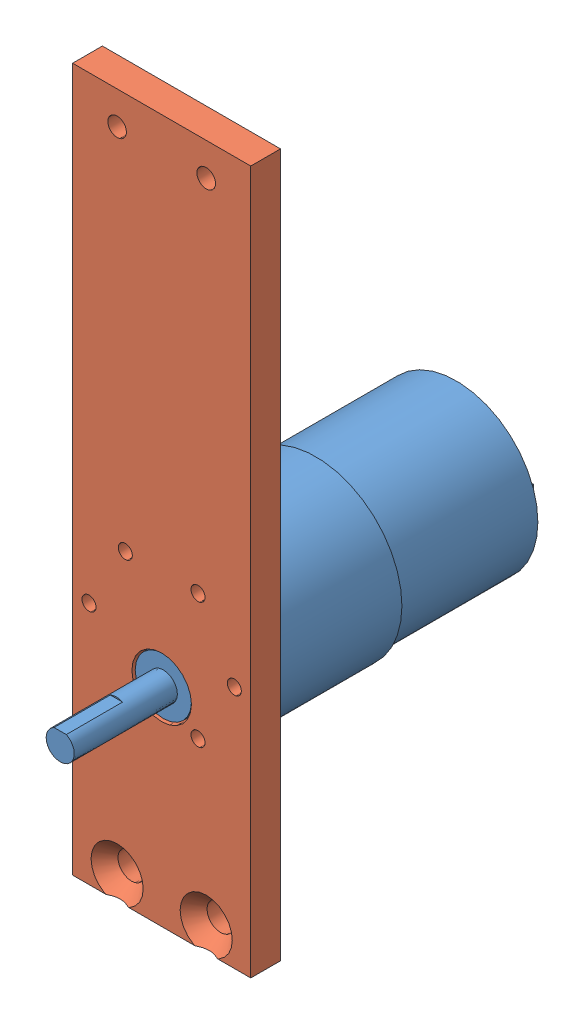
SolidWorks assembly Motor Montado, configuration Predeterminado. Lengths in mm.
Overall size (38 195 89.5).
2 component instances, 2 part files, 3 mates.
Components (placement in the parent):
- Motores Pololu-1: Motores Pololu [Predeterminado] at (-0.3863 2.7426 79.75) size (36.8 36.8 89.5)
- soporte motor-1: soporte motor [Predeterminado] at (-0.3863 25.7426 109.425) size (38 195 6.35)
Mates (geometry in assembly coordinates):
- Paralelo1: parallel aligned: cylinder of Motores Pololu-1 through (7.3637 16.166 101.25) axis (0 0 1) radius 1.5; cylinder of soporte motor-1 through (15.1137 2.7426 87.2) axis (0 0 1) radius 1.5
- Coincidente1: coincident anti-aligned: plane of Motores Pololu-1 through (-0.3863 2.7426 106.25) normal (0 0 1); plane of soporte motor-1 through (-0.3863 25.7426 106.25) normal (0 0 -1)
- Coincidente2: coincident anti-aligned: cylinder of Motores Pololu-1 through (15.1137 2.7426 101.25) axis (0 0 1) radius 1.5; circle of soporte motor-1
